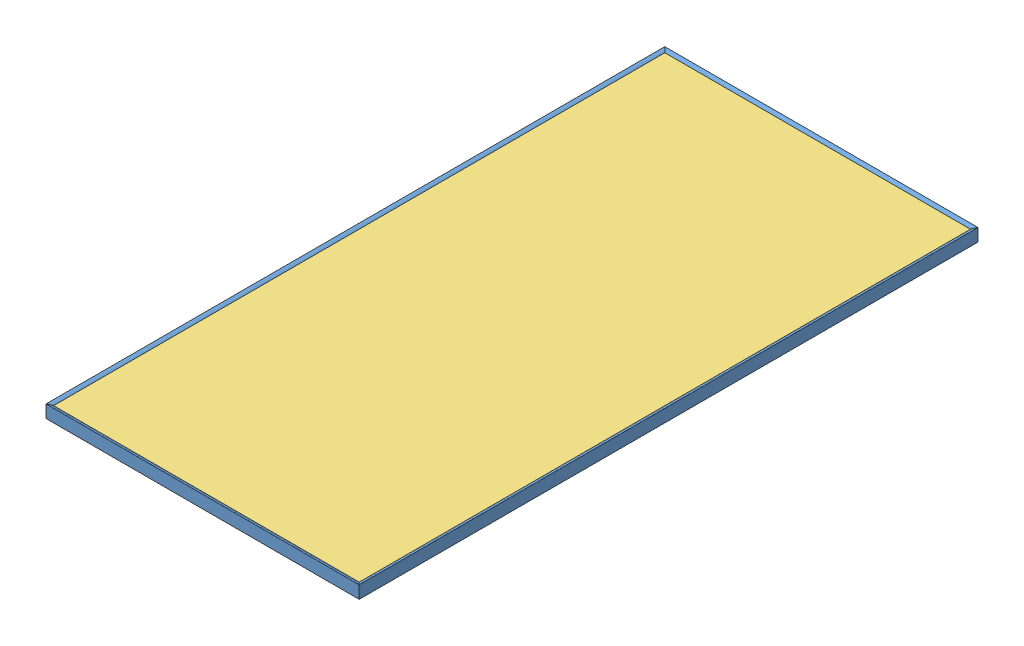
SolidWorks assembly SOLARPANEL, configuration Default. Lengths in mm.
Overall size (992.4 40.23 1960.4).
3 component instances, 3 part files, 6 mates.
Components (placement in the parent):
- SOLAR_PANEL_FRAM-1: SOLAR_PANEL_FRAM [Default] at origin size (992.4 40.23 1960.4)
- SOLAR_PANEL_CELL-1: SOLAR_PANEL_CELL [Default] at (395 11.5 868.9962) x (0 0 -1) z (1 0 0) size (1956 21.55 988)
- SOLAR_GLASS-1: SOLAR_GLASS [Default] at (0 11.8 0) x (0 0 1) z (-1 0 0) size (1956 3.2 988)
Mates (geometry in assembly coordinates):
- Coincident1: coincident anti-aligned: plane of SOLAR_PANEL_FRAM-1 through (-496.2 10.5 -978) normal (0 1 0); plane of SOLAR_PANEL_CELL-1 through (395 10.5 868.9962) normal (0 -1 0)
- Coincident2: coincident anti-aligned: plane of SOLAR_PANEL_FRAM-1 through (-496.2 15 -978) normal (0 0 1); plane of SOLAR_PANEL_CELL-1 through (-494 10.5 -978) normal (0 0 -1)
- Coincident3: coincident anti-aligned: plane of SOLAR_PANEL_FRAM-1 through (-494 15 980.2) normal (1 0 0); plane of SOLAR_PANEL_CELL-1 through (-494 10.5 -978) normal (-1 0 0)
- Coincident4: coincident anti-aligned: plane of SOLAR_PANEL_FRAM-1 through (496.2 15 978) normal (0 0 -1); plane of SOLAR_GLASS-1 through (494 15 978) normal (0 0 1)
- Coincident5: coincident anti-aligned: plane of SOLAR_PANEL_FRAM-1 through (494 15 -980.2) normal (-1 0 0); plane of SOLAR_GLASS-1 through (494 15 -978) normal (1 0 0)
- Coincident6: coincident anti-aligned: plane of SOLAR_PANEL_CELL-1 through (395 11.8 868.9962) normal (0 1 0); plane of SOLAR_GLASS-1 through (0 11.8 0) normal (0 -1 0)
